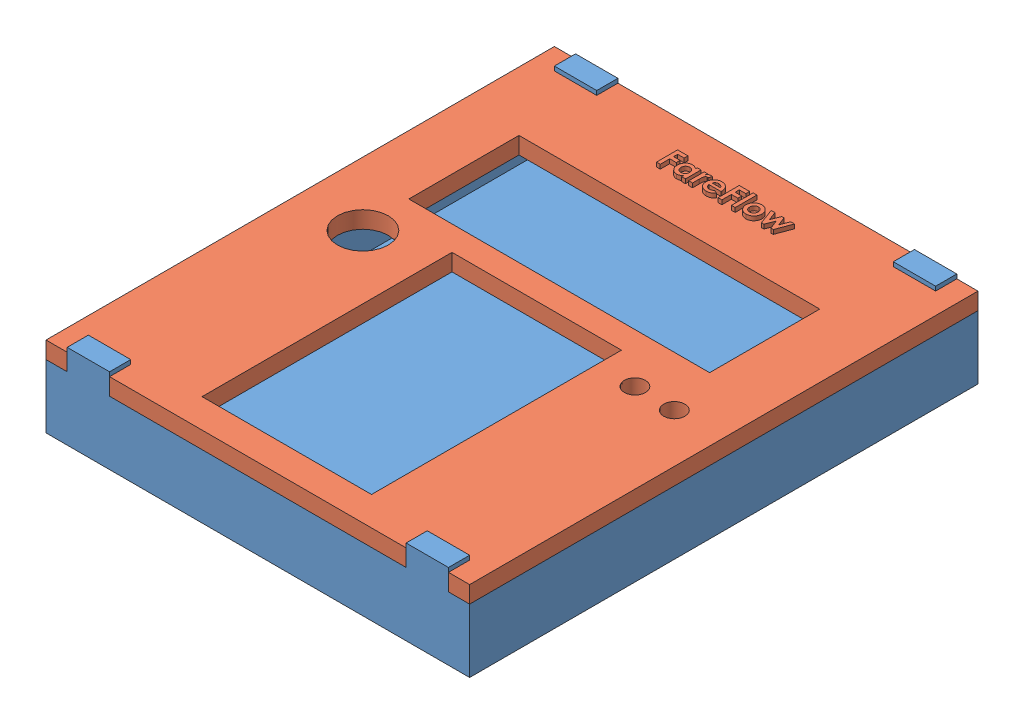
SolidWorks assembly Assem1, configuration Default. Lengths in mm.
Overall size (100 20 120).
2 component instances, 2 part files, 2 mates.
Components (placement in the parent):
- Bottom-1: Bottom [Default] at (48.0549 46.6361 101.2498) size (100 20 120)
- Top-1: Top [Default] at (48.0549 61.6361 101.2498) size (100 5 120)
Mates (geometry in assembly coordinates):
- Coincident1: coincident: line of Bottom-1 through (98.0549 61.6361 41.2498) axis (0 0 1); point of Top-1
- Coincident2: coincident aligned: line of Bottom-1 through (93.0549 61.6361 161.2498) axis (1 0 0); line of Top-1 through (93.0549 61.6361 161.2498) axis (1 0 0)
